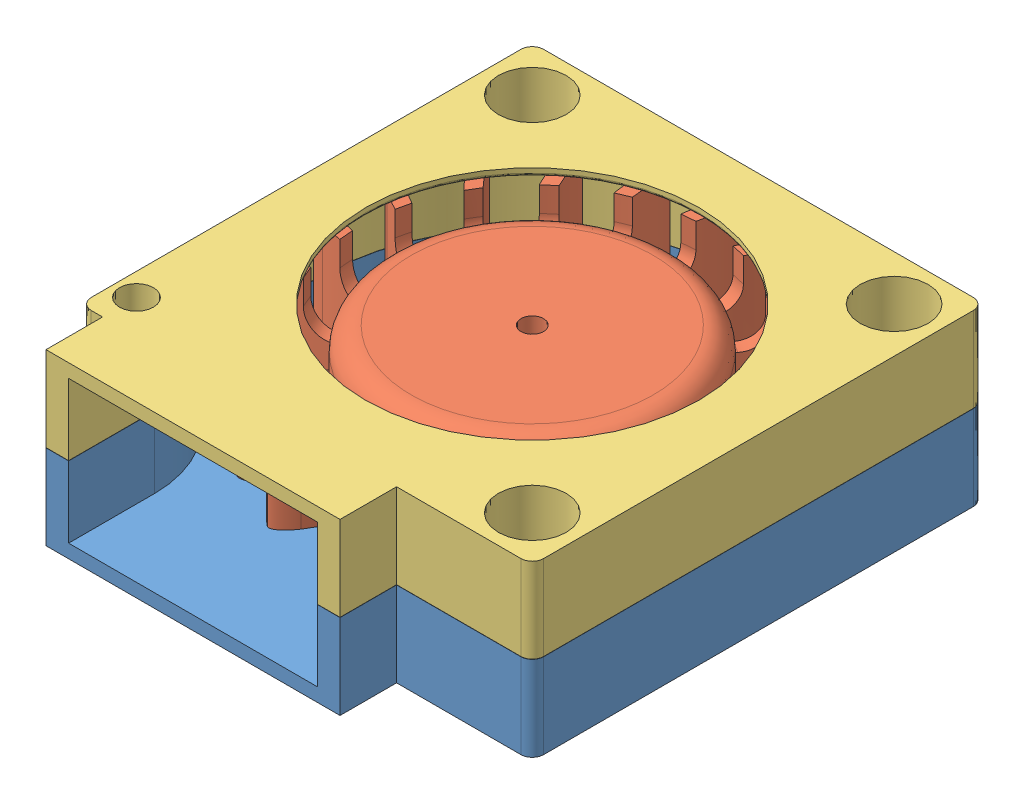
SolidWorks assembly Assem2, configuration Default. Lengths in mm.
Overall size (41.36 15.02 45.68).
3 component instances, 3 part files, 4 mates.
Components (placement in the parent):
- BODY2-1: BODY2 [Default] at (-54.8836 -24.2174 40.3189) size (40 7.5 45)
- Fan-1: Fan [Default] at (-54.8836 -20.0174 40.3189) x (0.118893 0 -0.992907) z (0.992907 0 0.118893) size (37.2 9.21 37.2)
- BODY COVER-1: BODY COVER [Default] at (-54.8836 -24.1977 40.3189) size (40 7.5 45)
Mates (geometry in assembly coordinates):
- Concentric1: concentric aligned: circle of BODY2-1; cylinder of Fan-1 through (-54.8836 -20.0174 40.3189) axis (0 1 0) radius 1
- Concentric2: concentric anti-aligned: cylinder of BODY2-1 through (-70.8836 -24.2174 24.3189) axis (0 1 0) radius 1.5; cylinder of BODY COVER-1 through (-70.8836 -9.1977 24.3189) axis (0 -1 0) radius 1.5
- Coincident2: coincident aligned: plane of BODY2-1 through (-74.8836 -16.7174 60.3189) normal (-1 0 0); plane of BODY COVER-1 through (-74.8836 -16.6977 60.3189) normal (-1 0 0)
- Distance2: distance = 3 mm anti-aligned: plane of BODY2-1 through (-54.8836 -23.0174 40.3189) normal (0 1 0); plane of Fan-1 through (-54.8836 -20.0174 40.3189) normal (0 -1 0)
